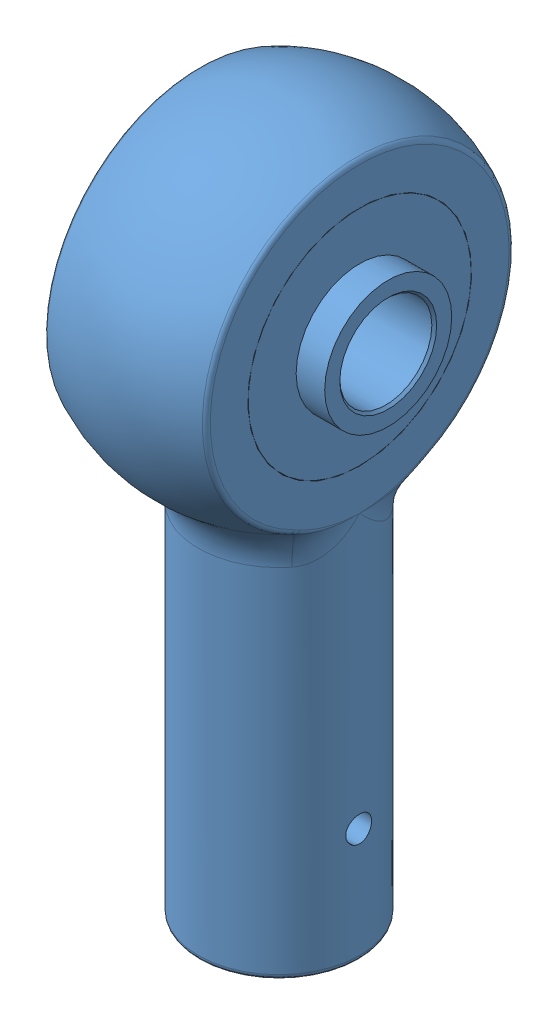
SolidWorks assembly REP4F5, configuration Default. Lengths in mm.
Overall size (15.06 49.23 23.83).
2 component instances, 1 part files, 1 mates.
Components (placement in the parent):
- REP4F5-1: REP4F5 [Body] at (4.5509 38.8285 36.1519) size (15.06 49.23 23.83)
- REP4F5-2: REP4F5 [Ball] at (4.5509 38.8285 36.1519) size (15.06 49.23 23.83)
Mates (geometry in assembly coordinates):
- Concentric1: concentric: sphere of REP4F5-1; sphere of REP4F5-2
